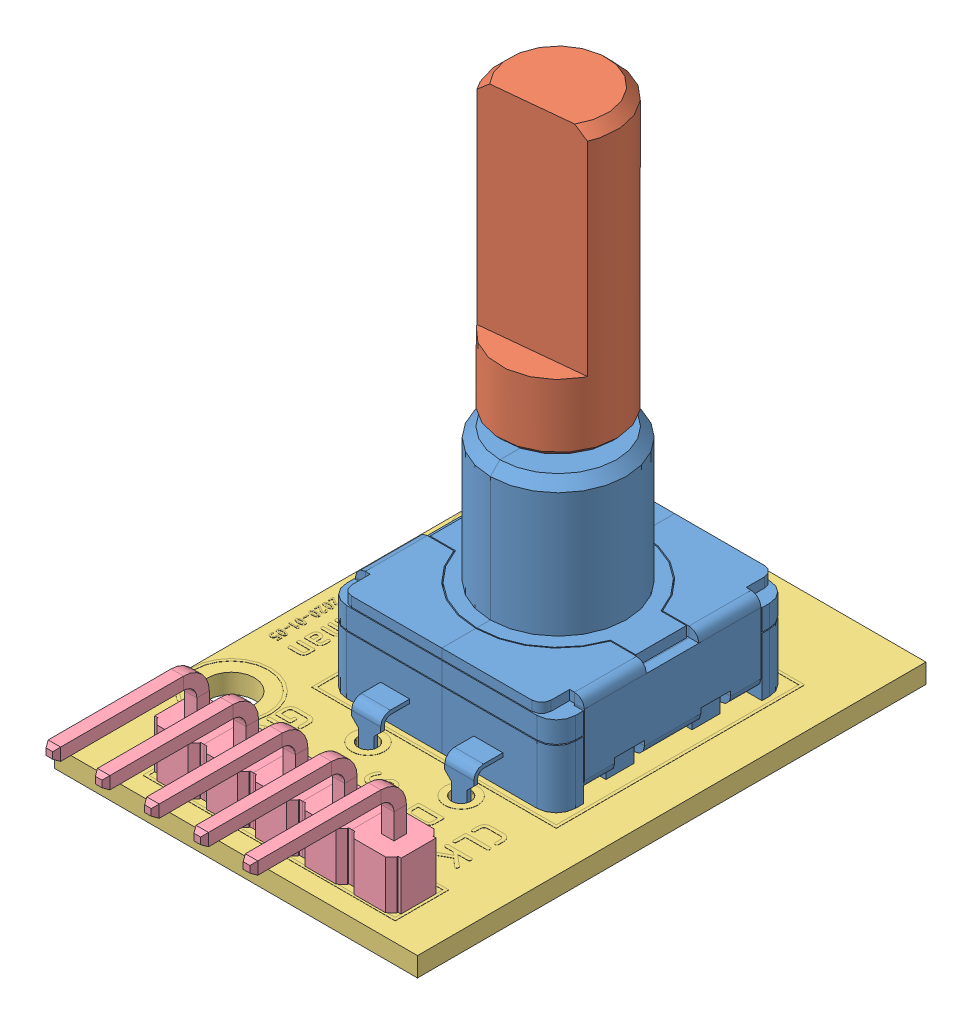
SolidWorks assembly KY-040 Rotary Encoder, configuration Default. Lengths in mm.
Overall size (18.7 30.1 31.47).
4 component instances, 4 part files, 8 mates.
Components (placement in the parent):
- Rotary Encoder-1: Rotary Encoder [Default] at (5.1929 2.265 12.688) size (11.8 14.9 15)
- D-handle-1: D-handle [Default] at (5.1929 8.865 12.688) x (-0.994918 0 0.100689) z (-0.100689 0 -0.994918) size (6 20.2 6)
- pcb-1: pcb [Default] at (-5.1071 1.765 2.138) x (0 0 1) z (-1 0 0) size (26.2 1.02 18.7)
- 2.54 5PIN 90-1: 2.54 5PIN 90 [Default] at (-0.1071 2.265 26.008) x (-1 0 0) z (0 0 -1) size (12.7 7.32 8.85)
Mates (geometry in assembly coordinates):
- 同心1: concentric: cylinder of Rotary Encoder-1 through (5.1929 8.865 12.688) axis (0 1 0) radius 1.425; cylinder of D-handle-1 through (5.1929 14.565 12.688) axis (0 -1 0) radius 1.3
- 重合2: coincident: plane of Rotary Encoder-1 through (5.1929 8.865 12.688) normal (0 1 0); plane of D-handle-1 through (5.1929 8.865 12.688) normal (0 -1 0)
- 距离2: distance = 4.4 mm: plane of pcb-1 through (-5.1071 1.265 2.138) normal (-1 0 0); plane of Rotary Encoder-1 through (-0.7071 2.265 12.688) normal (-1 0 0)
- 重合4: coincident: plane of Rotary Encoder-1 through (10.0929 2.265 17.688) normal (0 -1 0); plane of pcb-1 through (-5.1071 2.265 2.138) normal (0 1 0)
- 距离3: distance = 4.55 mm: plane of Rotary Encoder-1 through (0.2929 5.265 6.688) normal (0 0 -1); plane of pcb-1 through (-5.1071 1.265 2.138) normal (0 0 -1)
- 距离4: distance = 0.77 mm: plane of 2.54 5PIN 90-1 through (11.1529 4.765 27.258) normal (0 0 1); cylinder of pcb-1 through (10.0529 1.265 25.988) axis (0 -1 0) radius 0.5
- 重合6: coincident: plane of pcb-1 through (-5.1071 2.265 2.138) normal (0 1 0); plane of 2.54 5PIN 90-1 through (10.0529 2.265 26.008) normal (0 -1 0)
- 距离5: distance = 1.27 mm: plane of 2.54 5PIN 90-1 through (11.3229 4.765 25.108) normal (1 0 0); cylinder of pcb-1 through (10.0529 1.265 25.988) axis (0 -1 0) radius 0.5
